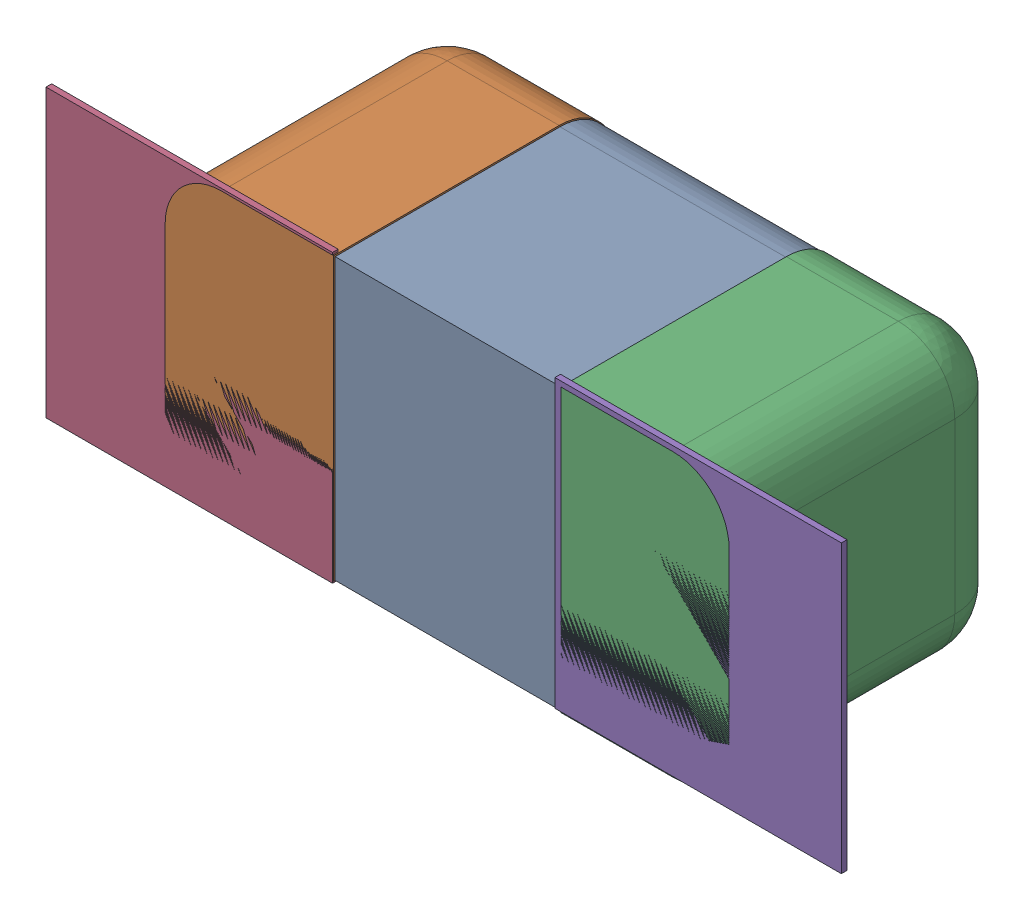
SolidWorks assembly C148, configuration Défaut. Lengths in mm.
Overall size (1.41 0.51 0.5).
8 component instances, 4 part files, 0 mates.
Components (placement in the parent):
- 5458962032-1: 5458962032 [Défaut] at (4.9784 -0.089 -2.0818) x (1 0 0) z (0 1 0) size (1 0.5 0.5)
  - Open CASCADE STEP translator 7.5 2.80.1.1-1: Open CASCADE STEP translator 7.5 2.80.1.1 [Défaut] at origin size (0.4 0.5 0.5)
  - Open CASCADE STEP translator 7.5 2.80.1.2-1: Open CASCADE STEP translator 7.5 2.80.1.2 [Défaut] at origin size (0.3 0.5 0.5)
  - Open CASCADE STEP translator 7.5 2.80.1.3-1: Open CASCADE STEP translator 7.5 2.80.1.3 [Défaut] at origin size (0.3 0.5 0.5)
- 6504207776-1: 6504207776 [Défaut] at (4.5211 -0.089 -2.0918) size (0.51 0.51 0.01)
  - Extruded-1: Extruded [Défaut] at origin size (0.51 0.51 0.01)
- 6504207776-2: 6504207776 [Défaut] at (5.4234 -0.0838 -2.0918) size (0.51 0.51 0.01)
  - Extruded-1: Extruded [Défaut] at origin size (0.51 0.51 0.01)
